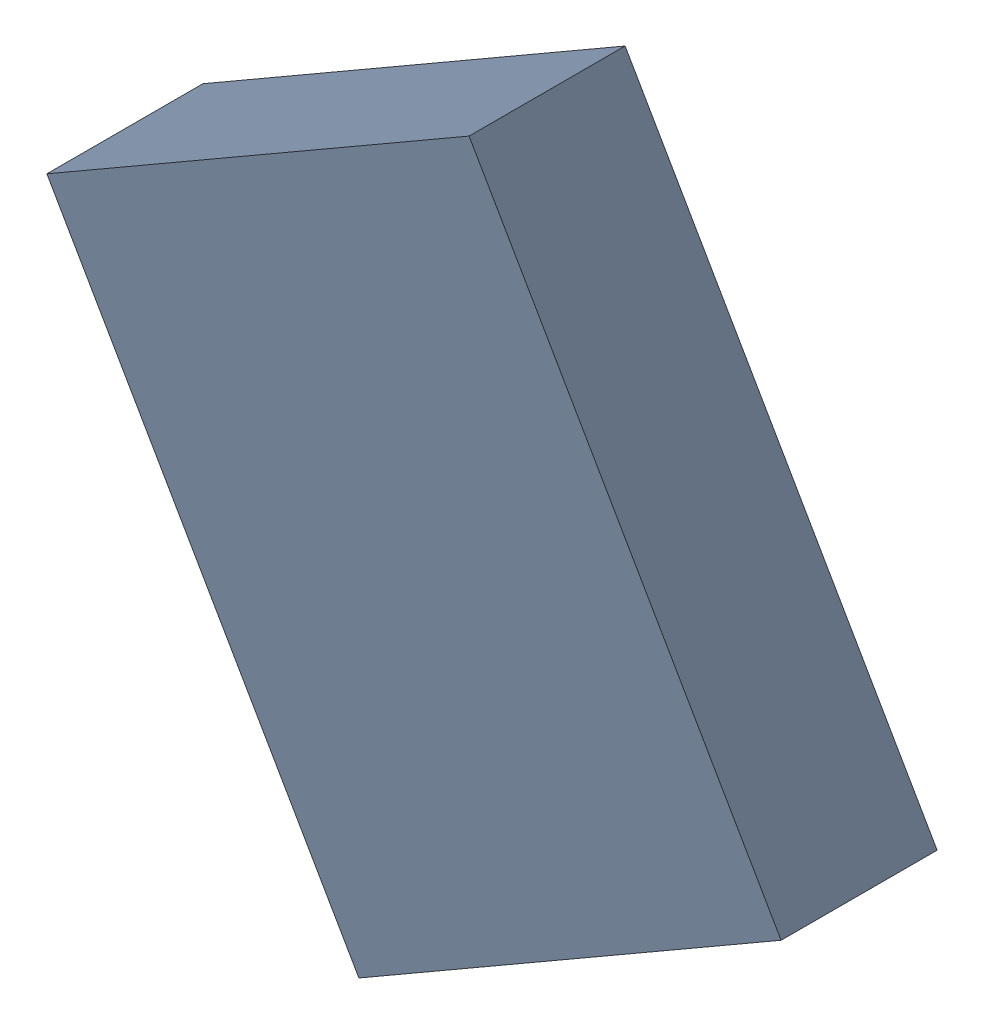
SolidWorks assembly X_TDA_TDA2, configuration Standard. Lengths in mm.
Overall size (3.77 4.02 0.8).
2 component instances, 1 part files, 0 mates.
Components (placement in the parent):
- 885545640-1: 885545640 [Standard] at (34.8045 23.5121 0) size (3.77 4.02 0.8)
  - Extruded_2-1: Extruded_2 [Standard] at origin size (3.77 4.02 0.8)
